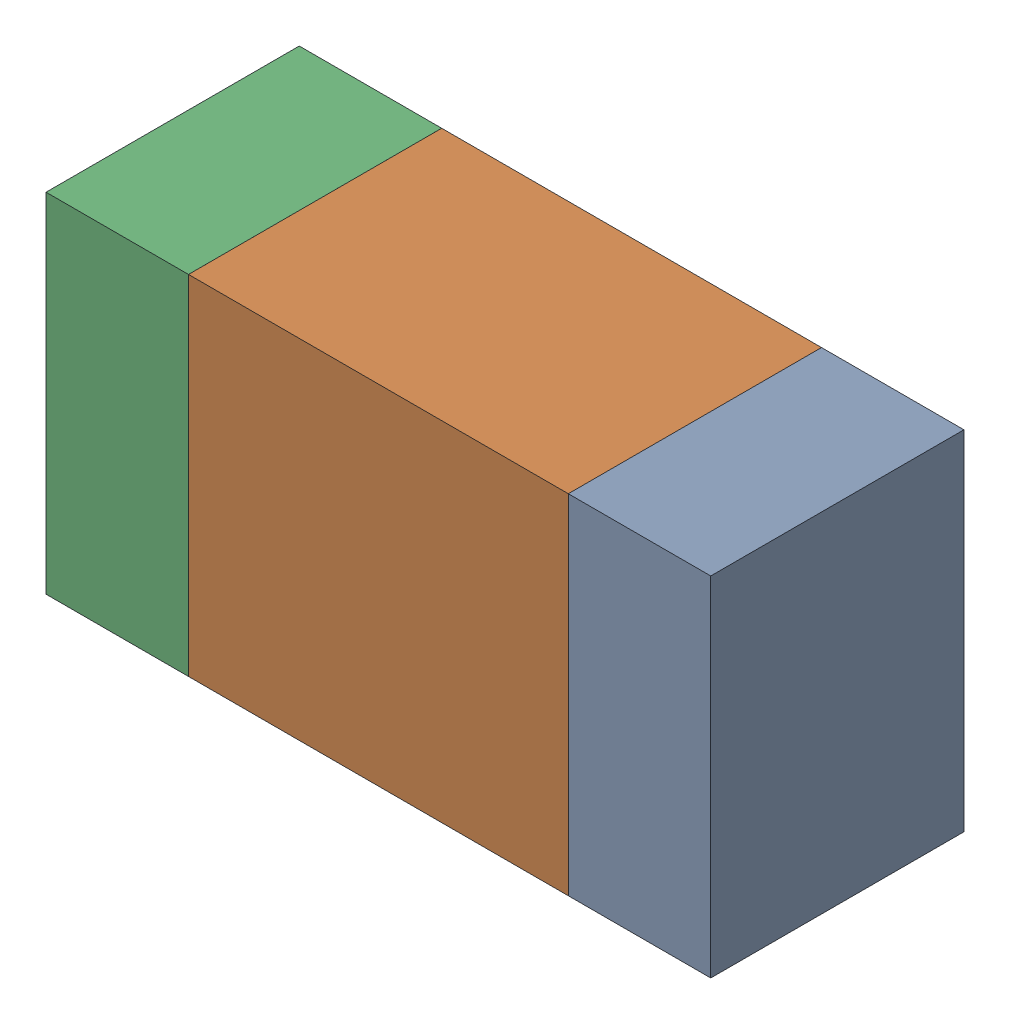
SolidWorks assembly R322_1PCB, configuration Default. Lengths in mm.
Overall size (1.05 0.55 0.4).
6 component instances, 2 part files, 0 mates.
Components (placement in the parent):
- 854785432-1: 854785432 [Default] at (139.5124 117.7999 -2.0638) size (0.22 0.55 0.4)
  - Extruded-1: Extruded [Default] at origin size (0.22 0.55 0.4)
- 854785568-1: 854785568 [Default] at (139.0999 117.7999 -2.0638) size (0.6 0.55 0.4)
  - Extruded_2-1: Extruded_2 [Default] at origin size (0.6 0.55 0.4)
- 854785432-2: 854785432 [Default] at (138.6874 117.7999 -2.0638) size (0.22 0.55 0.4)
  - Extruded-1: Extruded [Default] at origin size (0.22 0.55 0.4)
